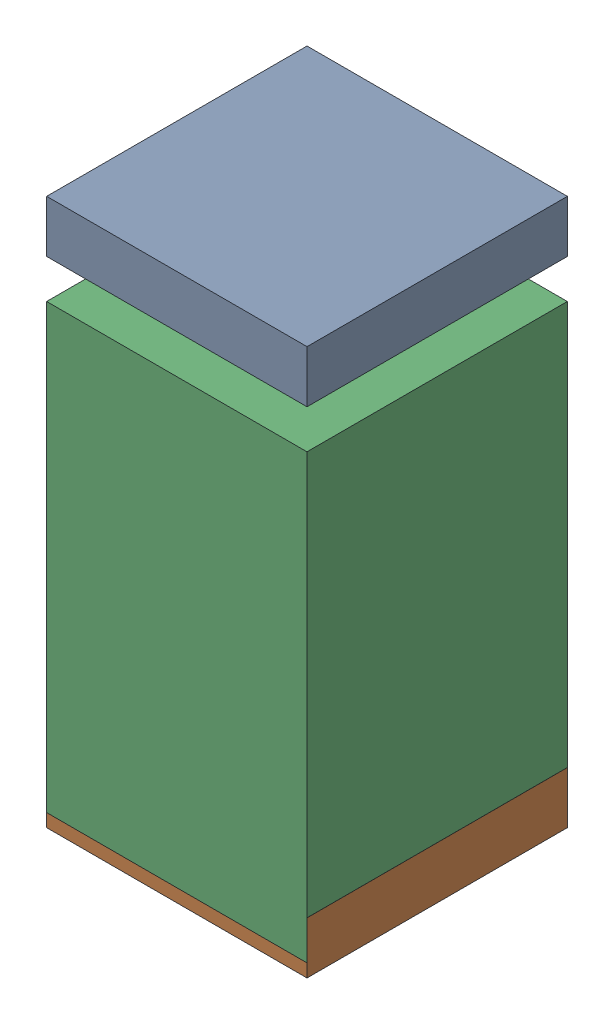
SolidWorks assembly C29, configuration Default. Lengths in mm.
Overall size (0.5 1.05 0.5).
6 component instances, 2 part files, 0 mates.
Components (placement in the parent):
- 810157360-1: 810157360 [Default] at (129.75 27.9 0) size (0.5 0.1 0.5)
  - Extruded_9-1: Extruded_9 [Default] at origin size (0.5 0.1 0.5)
- 810157360-2: 810157360 [Default] at (129.75 26.95 0) size (0.5 0.1 0.5)
  - Extruded_9-1: Extruded_9 [Default] at origin size (0.5 0.1 0.5)
- 810157104-1: 810157104 [Default] at (129.7499 27.3501 0) size (0.5 0.85 0.5)
  - Extruded_16-1: Extruded_16 [Default] at origin size (0.5 0.85 0.5)
